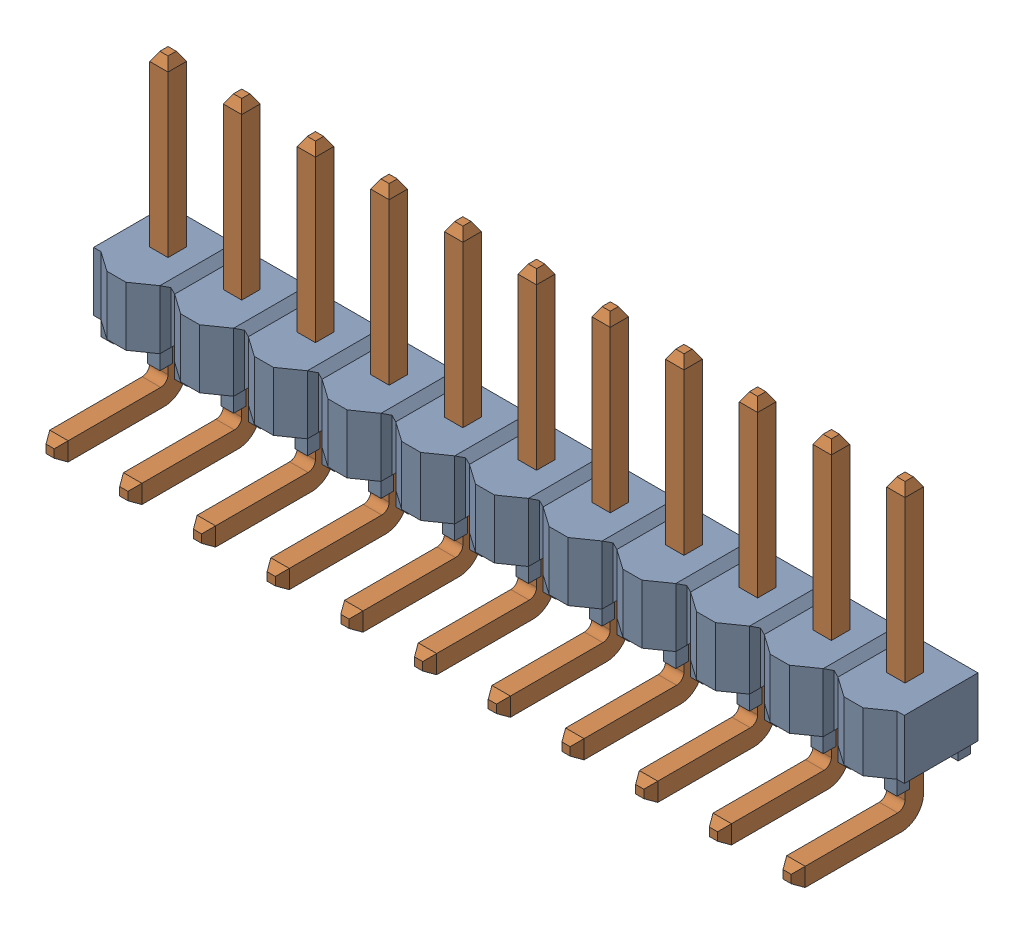
SolidWorks assembly TSW_111_08_G_S_RA, configuration Default. Lengths in mm.
Overall size (27.94 10.22 5.31).
2 component instances, 2 part files, 0 mates.
Components (placement in the parent):
- _TSW_111_08_G_S_RA_body_2-1: _TSW_111_08_G_S_RA_body_2 [Default] at origin size (27.94 2.54 3.02)
- _T_1S6_08_TSW_1_08_11_RA_S_4-1: _T_1S6_08_TSW_1_08_11_RA_S_4 [Default] at (0 -1.524 -0.0254) size (26.29 10.22 4.51)
